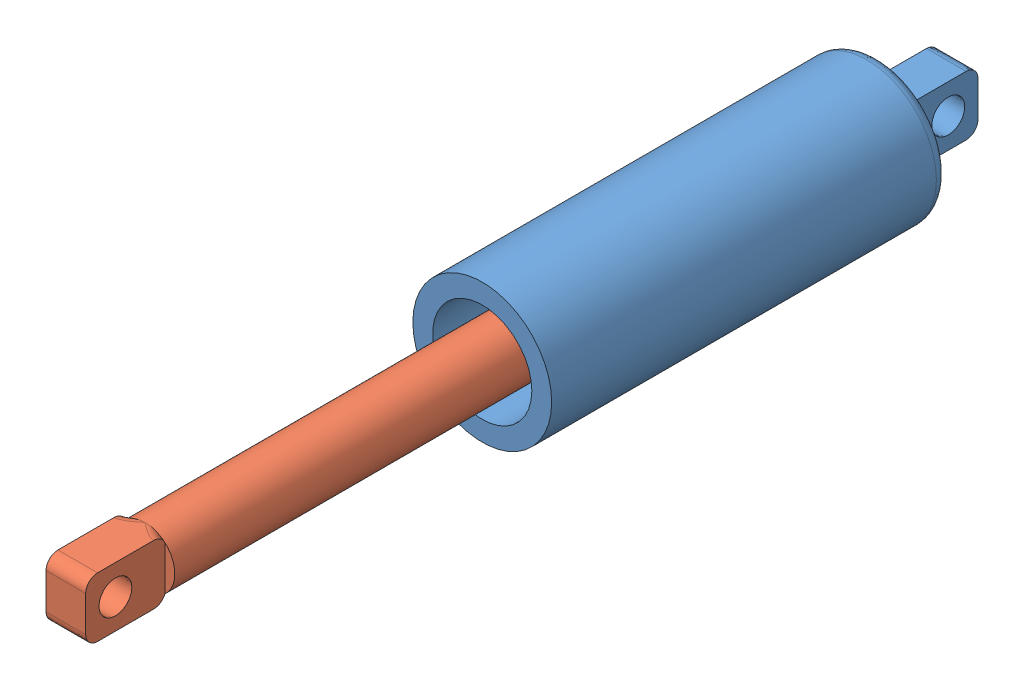
SolidWorks assembly DamperAssy, configuration Default. Lengths in mm.
Overall size (35 35 225).
2 component instances, 2 part files, 4 mates.
Components (placement in the parent):
- DamperCylinder-1: DamperCylinder [Default] at origin size (35 35 120)
- DamperPiston-1: DamperPiston [Default] at (0 0 80) x (0 -1 0) z (0 0 1) size (25 25 125)
Mates (geometry in assembly coordinates):
- Coincident1: coordinate: point of assembly; point of DamperCylinder-1; point of assembly
- Concentric1: concentric: cylinder of DamperCylinder-1 through (0 0 10) axis (0 0 1) radius 12.5; cylinder of DamperPiston-1 through (0 0 85) axis (0 0 -1) radius 12.5
- Coincident2: coincident: plane of DamperCylinder-1 through (5 0 0) normal (1 0 0); plane of DamperPiston-1 through (5 0 80) normal (1 0 0)
- Distance1: distance = 70 mm: plane of DamperPiston-1 through (0 0 80) normal (0 0 -1); plane of DamperCylinder-1 through (0 0 10) normal (0 0 1)
